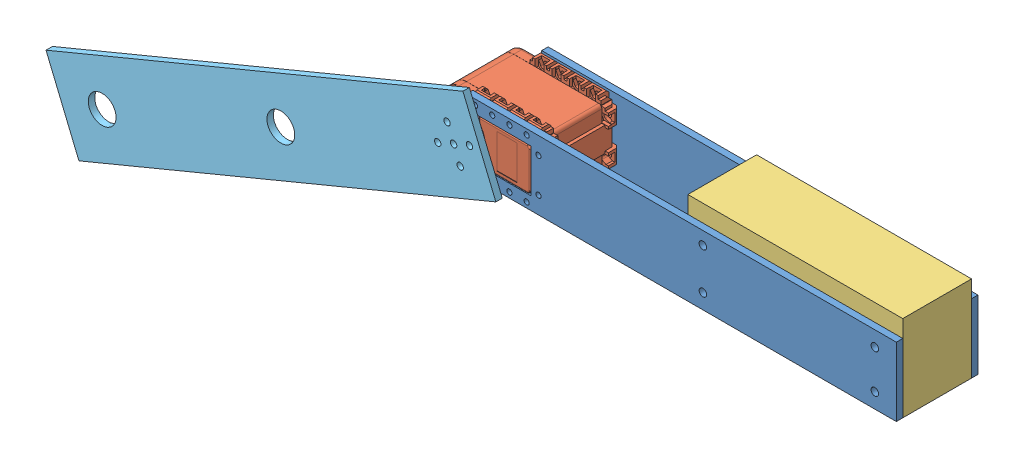
SolidWorks assembly Testrig, configuration Default. Lengths in mm.
Overall size (391.53 121 42.44).
7 component instances, 6 part files, 14 mates.
Components (placement in the parent):
- Servo holder-1: Servo holder [Défaut] at (6.0494 125.452 175.397) size (200 33 3)
- Servo holder-2: Servo holder [Défaut] at (6.0494 125.452 210.397) size (200 33 3)
- ServoBody-1: ServoBody [Default] at (-14.2006 124.952 207.797) x (0 1 0) z (0 0 1) size (32 50.04 38.67)
- distbox-1: distbox [Default] at (138.2994 129.452 178.397) size (100 40 32)
- ServoHorn-1: ServoHorn [Default] at (-14.2006 125.452 193.627) x (0 1 0) z (0 0 1) size (22 22 6.71)
- ServoWheel-1: ServoWheel [Default] at (-14.8108 128.5164 239.367) x (-0.923728 -0.383049 0) z (0 0 -1) size (44 44 10.71) (hidden)
- ServoRod-1: ServoRod [Default] at (-10.8193 123.5368 217.497) x (-0.923728 -0.383049 0) z (0 0 -1) size (210 40 3)
Mates (geometry in assembly coordinates):
- Coincident1: coincident anti-aligned: plane of Servo holder-2 through (6.0494 125.452 210.397) normal (0 0 -1); plane of distbox-1 through (138.2994 129.452 210.397) normal (0 0 1)
- Coincident2: coincident aligned: plane of Servo holder-2 through (188.2994 141.452 213.397) normal (1 0 0); plane of distbox-1 through (188.2994 109.452 210.397) normal (1 0 0)
- Coincident3: coincident aligned: plane of Servo holder-2 through (188.2994 109.452 213.397) normal (0 -1 0); plane of distbox-1 through (88.2994 109.452 210.397) normal (0 -1 0)
- Coincident4: coincident anti-aligned: plane of Servo holder-1 through (6.0494 125.452 178.397) normal (0 0 1); plane of distbox-1 through (138.2994 129.452 178.397) normal (0 0 -1)
- Coincident5: coincident aligned: plane of Servo holder-1 through (188.2994 141.452 178.397) normal (1 0 0); plane of distbox-1 through (188.2994 109.452 210.397) normal (1 0 0)
- Coincident6: coincident aligned: plane of Servo holder-1 through (188.2994 109.452 178.397) normal (0 -1 0); plane of distbox-1 through (88.2994 109.452 210.397) normal (0 -1 0)
- Concentric1: concentric aligned: cylinder of Servo holder-2 through (21.7994 133.452 213.397) axis (0 0 1) radius 1.2; cylinder of ServoBody-1 through (21.7994 133.452 208.397) axis (0 0 1) radius 1.1
- Concentric2: concentric anti-aligned: cylinder of Servo holder-2 through (21.7994 117.452 213.397) axis (0 0 1) radius 1.2; cylinder of ServoBody-1 through (21.7994 117.452 210.197) axis (0 0 -1) radius 1.1
- Coincident7: coincident anti-aligned: plane of Servo holder-2 through (6.0494 125.452 210.397) normal (0 0 -1); plane of ServoBody-1 through (24.0824 109.956 210.397) normal (0 0 1)
- Concentric8: concentric anti-aligned: cylinder of ServoBody-1 through (-14.2006 125.452 207.797) axis (0 0 1) radius 4.6; cone of ServoHorn-1 through (-14.2006 125.452 210.657) axis (0 0 -1)
- Concentric9: concentric: cylinder of ServoHorn-1 through (-22.2006 125.452 212.657) axis (0 0 1) radius 1.05; cylinder of ServoWheel-1 through (-22.2006 125.452 218.497) axis (0 0 1) radius 1.2
- Coincident10: coincident anti-aligned: plane of ServoHorn-1 through (-25.6378 114.0092 214.497) normal (0 0 1); plane of ServoWheel-1 through (-14.8108 128.5164 214.497) normal (0 0 -1)
- Concentric10: concentric: cylinder of ServoHorn-1 through (-6.2006 125.452 212.657) axis (0 0 1) radius 1.05; cylinder of ServoRod-1 through (-6.2006 125.452 217.497) axis (0 0 1) radius 1.5
- Coincident11: coincident anti-aligned: plane of ServoHorn-1 through (-25.6378 114.0092 214.497) normal (0 0 1); plane of ServoRod-1 through (-10.8193 123.5368 214.497) normal (0 0 -1)
